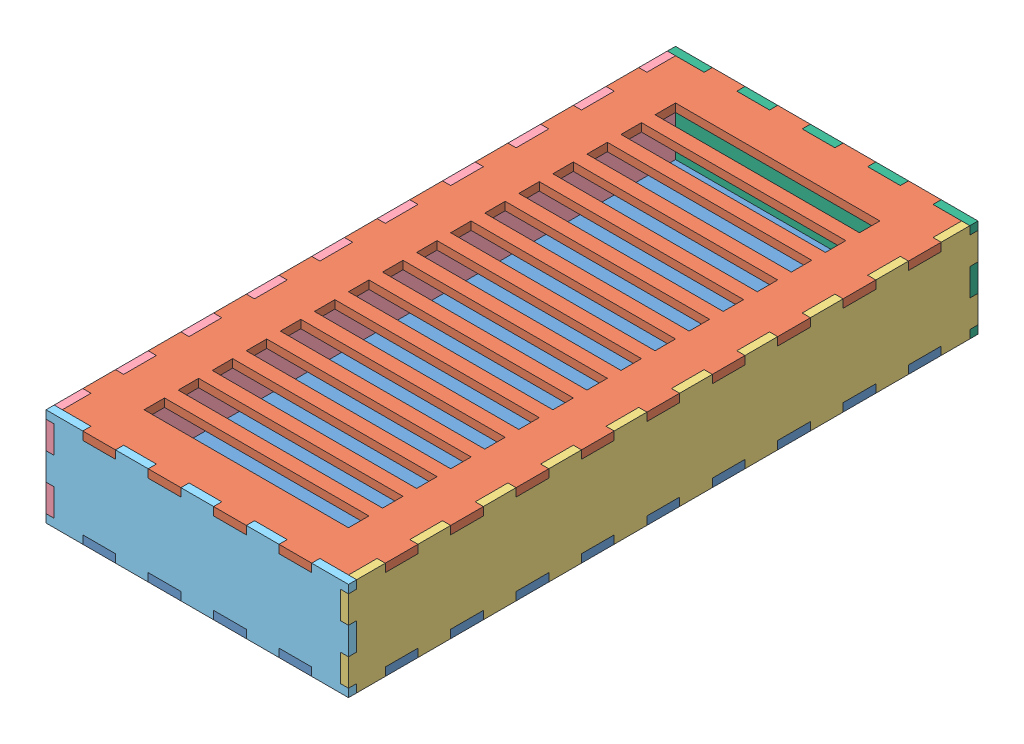
SolidWorks assembly Assem1, configuration Default. Lengths in mm.
Overall size (222 72 462).
6 component instances, 6 part files, 17 mates.
Components (placement in the parent):
- onderkant-1: onderkant [Default] at (-45.1781 12.9606 12.9965) size (222 6 462)
- bovenkant-1: bovenkant [Default] at (-45.1781 78.9606 12.9965) size (222 6 462)
- lange_zijkant2-1: lange_zijkant2 [Default] at (59.8219 12.9606 12.9965) x (0 0 -1) z (1 0 0) size (462 72 6)
- lange_zijkant1-2: lange_zijkant1 [Default] at (-156.1781 12.9606 12.9965) x (0 0 -1) z (1 0 0) size (462 72 6)
- voorkant-1: voorkant [Default] at (-45.1781 12.9606 237.9965) size (222 72 6)
- achterkant-1: achterkant [Default] at (-45.1781 12.9606 -218.0035) size (222 72 6)
Mates (geometry in assembly coordinates):
- InPlace1: in place: plane of onderkant-1 through (59.8219 18.9606 237.9965) normal (1 0 0); plane of ? through (59.8219 0 0) normal (1 0 0); moOrthogonalPlaneRef_w of onderkant-1 through (59.8219 18.9606 237.9965) normal (1 0 0); plane of ? through (59.8219 0 0) normal (0 1 0); plane of onderkant-1 through (59.8219 18.9606 237.9965) normal (1 0 0); plane of ? through (59.8219 0 0) normal (0 0 -1); plane of onderkant-1 through (59.8219 18.9606 237.9965) normal (1 0 0); unknown of lange_zijkant2-1
- Coincident1: coincident aligned: plane of ?; plane of ?
- Coincident2: coincident aligned: moOrthogonalPlaneRef_w of onderkant-1 through (59.8219 12.9606 12.9965) normal (0 1 0); plane of Part2^Assem1-1 through (59.8219 12.9606 12.9965) normal (0 1 0)
- Coincident3: coincident anti-aligned: moOrthogonalPlaneRef_w of onderkant-1 through (59.8219 12.9606 12.9965) normal (0 0 1); plane of Part2^Assem1-1 through (59.8219 12.9606 12.9965) normal (0 0 -1)
- Coincident4: coincident anti-aligned: plane of bovenkant-1 through (65.8219 78.9606 216.9965) normal (0 0 1); plane of lange_zijkant2-1 through (65.8219 12.9606 216.9965) normal (0 0 -1)
- Coincident5: coincident anti-aligned: plane of bovenkant-1 through (-45.1781 78.9606 12.9965) normal (0 -1 0); plane of lange_zijkant2-1 through (65.8219 78.9606 12.9965) normal (0 1 0)
- Coincident6: coincident anti-aligned: plane of bovenkant-1 through (-150.1781 78.9606 192.9965) normal (0 0 -1); plane of lange_zijkant1-2 through (-150.1781 12.9606 192.9965) normal (0 0 1)
- Coincident7: coincident anti-aligned: plane of bovenkant-1 through (-150.1781 84.9606 237.9965) normal (-1 0 0); plane of lange_zijkant1-2 through (-150.1781 12.9606 12.9965) normal (1 0 0)
- Coincident8: coincident anti-aligned: plane of bovenkant-1 through (-45.1781 78.9606 12.9965) normal (0 -1 0); plane of lange_zijkant1-2 through (-150.1781 78.9606 12.9965) normal (0 1 0)
- InPlace2: in place: plane of onderkant-1 through (-150.1781 18.9606 237.9965) normal (0 0 1); plane of ? through (0 0 237.9965) normal (0 0 1); plane of onderkant-1 through (-150.1781 18.9606 237.9965) normal (0 0 1); plane of ? through (0 0 237.9965) normal (0 1 0); plane of onderkant-1 through (-150.1781 18.9606 237.9965) normal (0 0 1); plane of ? through (0 0 237.9965) normal (1 0 0); plane of onderkant-1 through (-150.1781 18.9606 237.9965) normal (0 0 1); unknown of voorkant-1
- Coincident9: coincident aligned: plane of ?; plane of ?
- Coincident10: coincident aligned: moOrthogonalPlaneRef_w of onderkant-1 through (-45.1781 12.9606 237.9965) normal (0 1 0); plane of Part3^Assem1-1 through (-45.1781 12.9606 237.9965) normal (0 1 0)
- Coincident11: coincident anti-aligned: moOrthogonalPlaneRef_w of onderkant-1 through (-45.1781 12.9606 237.9965) normal (-1 0 0); plane of Part3^Assem1-1 through (-45.1781 12.9606 237.9965) normal (1 0 0)
- Coincident12: coincident anti-aligned: plane of bovenkant-1 through (59.8219 84.9606 237.9965) normal (1 0 0); plane of lange_zijkant2-1 through (59.8219 12.9606 12.9965) normal (-1 0 0)
- Coincident13: coincident: plane of bovenkant-1 through (38.8219 78.9606 12.9965) normal (1 0 0); plane of achterkant-1 through (38.8219 78.9606 -212.0035) normal (-1 0 0)
- Coincident14: coincident: plane of lange_zijkant2-1 through (65.8219 12.9606 -212.0035) normal (0 0 -1); plane of achterkant-1 through (-45.1781 12.9606 -212.0035) normal (0 0 1)
- Coincident15: coincident anti-aligned: plane of lange_zijkant2-1 through (59.8219 78.9606 -218.0035) normal (0 1 0); plane of achterkant-1 through (65.8219 78.9606 -212.0035) normal (0 -1 0)
